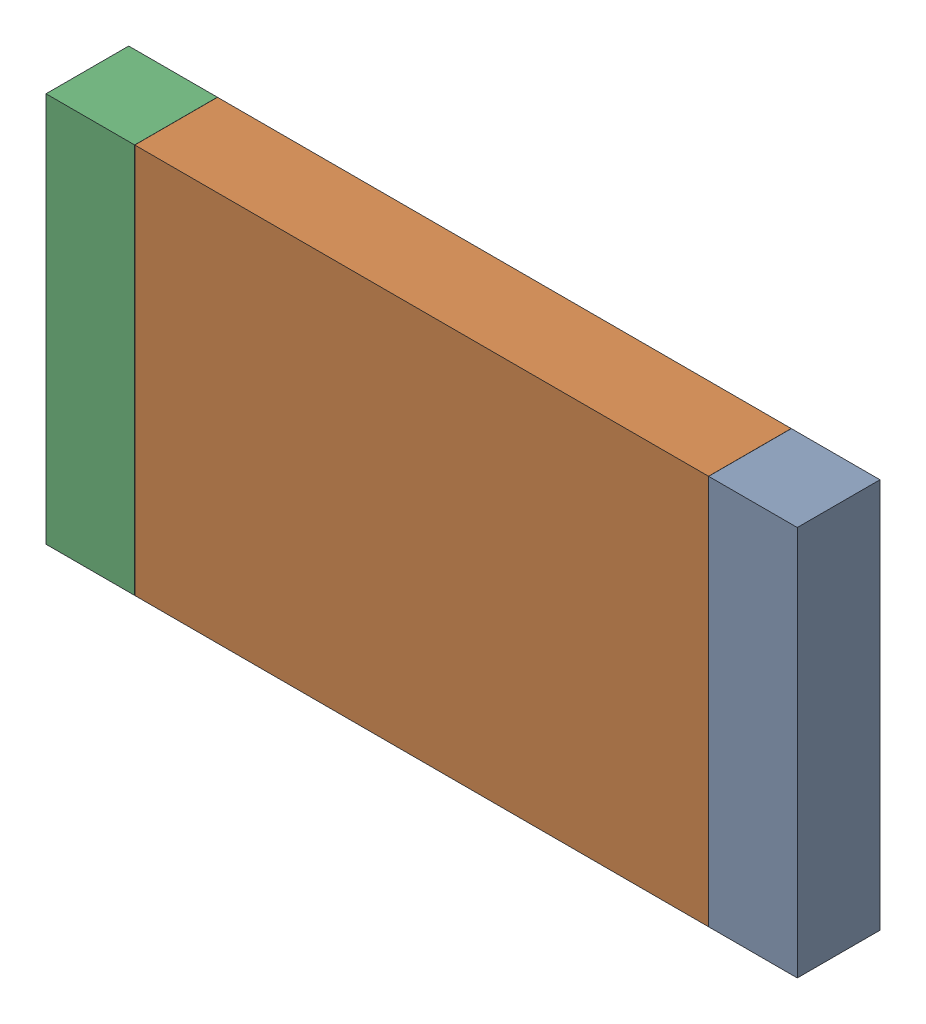
SolidWorks assembly R8, configuration Default. Lengths in mm.
Overall size (6.45 3.35 0.71).
6 component instances, 2 part files, 0 mates.
Components (placement in the parent):
- 6638401968-1: 6638401968 [Default] at (30.657 35.814 0) size (0.76 3.35 0.71)
  - Extruded_10-1: Extruded_10 [Default] at origin size (0.76 3.35 0.71)
- 6638401808-1: 6638401808 [Default] at (27.813 35.814 0) size (4.92 3.35 0.71)
  - Extruded_11-1: Extruded_11 [Default] at origin size (4.92 3.35 0.71)
- 6638401968-2: 6638401968 [Default] at (24.969 35.814 0) size (0.76 3.35 0.71)
  - Extruded_10-1: Extruded_10 [Default] at origin size (0.76 3.35 0.71)
